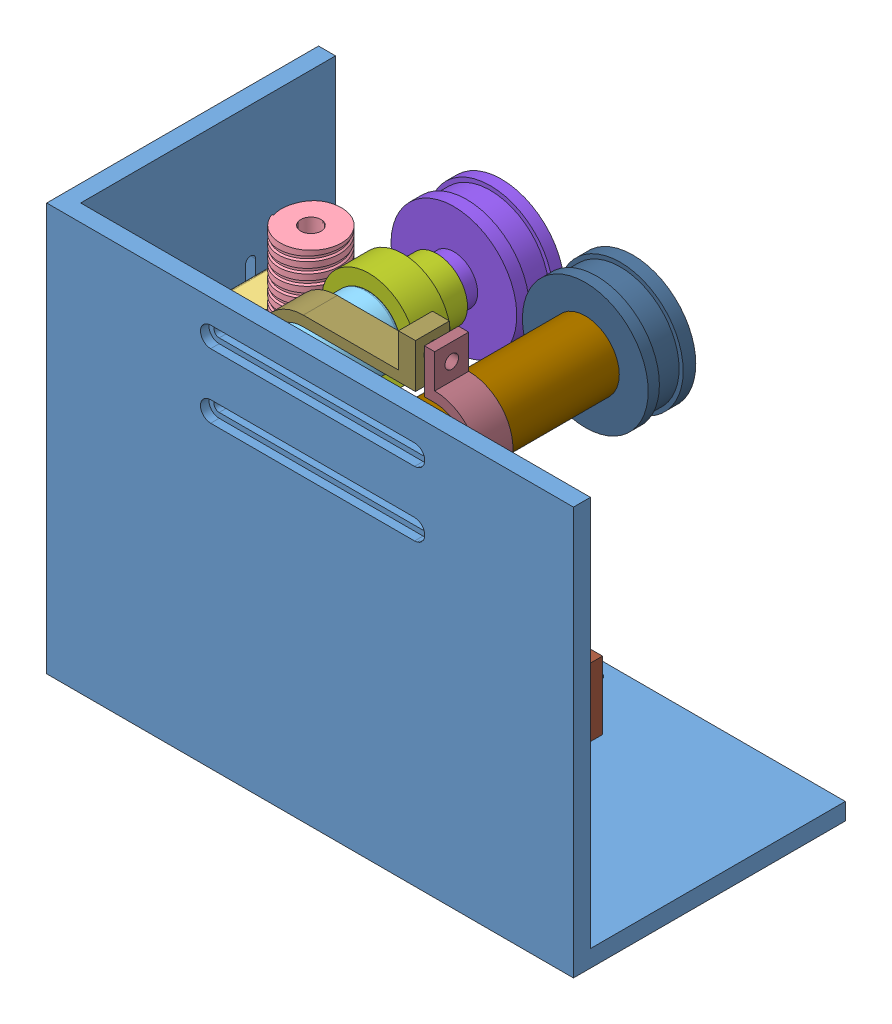
SolidWorks assembly 装配体2, configuration 默认. Lengths in mm.
Overall size (155 126.36 80).
18 component instances, 13 part files, 36 mates.
Components (placement in the parent):
- 支架-1: 支架 [默认] at origin size (155 120 80)
- 装配体-1: 装配体 [默认] at (30.5 -45.1244 40) x (-1 0 0) z (0 0 -1) size (45.5 73.2 40)
  - 电机-1: 电机 [默认] at origin size (36.5 73.2 36.5)
  - 电机支架-1: 电机支架 [默认] at (25.5 1.5 20) x (0 -1 0) z (0 0 -1) size (41 45.5 40)
- 蜗杆-1: 蜗杆 [默认] at (37.75 -38.8244 40) x (-0.943371 0 0.331739) z (0 1 0) size (18.01 18.93 32.45)
- 涡轮底座-1: 涡轮底座 [默认] at (72.3246 -7 72) x (0 -1 0) z (0 0 1) size (25 25 38)
- 轴承_8_12_3.5-2: 轴承_8_12_3.5 [默认] at (59.8246 -19.5 41) size (12 12 4)
- 蜗轮-2: 蜗轮 [默认] at (59.8246 -19.5 45) x (0.997228 0.0744 0) z (0 0 -1) size (28 28 20)
- 轮盘(3)-1: 轮盘(3) [默认] at (59.8246 -19.5 20) x (-0.591018 -0.806658 0) z (0 0 -1) size (37 37 31)
- 从动轮底座-1: 从动轮底座 [默认] at (85.9925 -7 72) size (25 25 67)
- 轮盘(1)-1: 轮盘(1) [默认] at (98.4925 -19.5 6) x (0.999997 0.002405 0) z (0 0 1) size (37 37 14)
- 轴承_8_12_3.5-4: 轴承_8_12_3.5 [默认] at (98.4925 -19.5 16) size (12 12 4)
- 深孔支架-1: 深孔支架 [默认] at (61.25 -115 23.6789) x (1 0 0) z (0 1 0) size (61 20 40)
- 轴承_8_12_3.5-3: 轴承_8_12_3.5 [默认] at (59.8246 -19.5 37) size (12 12 4)
- 轴承_8_12_3.5-5: 轴承_8_12_3.5 [默认] at (98.4925 -19.5 12) size (12 12 4)
- 轴承_8_12_3.5-6: 轴承_8_12_3.5 [默认] at (98.4925 -19.5 8) size (12 12 4)
- 紧固装置1-1: 紧固装置1 [默认] at (59.8246 -19.5 54.3149) size (46 46 10)
- 紧固装置2-1: 紧固装置2 [默认] at (98.4925 -19.5 64.3149) x (-1 0 0) z (0 0 -1) size (16 46 10)
Mates (geometry in assembly coordinates):
- 重合1: coincident anti-aligned: plane of 支架-1 through (5 0 80) normal (1 0 0); plane of 装配体-1/电机支架-1 through (5 -84.6244 20) normal (-1 0 0)
- 平行1: parallel aligned: plane of 支架-1 through (0 0 80) normal (0 1 0); plane of 装配体-1/电机支架-1 through (30.5 -43.6244 40) normal (0 1 0)
- 槽口1: slot anti-aligned: cylinder of 装配体-1/电机支架-1 through (5 -52.6244 55) axis (-1 0 0) radius 1.85; plane of 支架-1 through (-0.001 -40 53.5) normal (0 0 1); cylinder of 支架-1 through (-0.001 -80 55) axis (1 0 0) radius 1.5
- 重合3: coincident anti-aligned: plane of 装配体-1/电机-1 through (36.1423 -38.8244 40) normal (0 1 0); plane of 蜗杆-1 through (37.75 -38.8244 40) normal (0 -1 0)
- 同心4: concentric anti-aligned: cylinder of 装配体-1/电机-1 through (37.75 -38.8244 40) axis (0 1 0) radius 3; cylinder of 蜗杆-1 through (37.75 -6.3742 40) axis (0 -1 0) radius 3
- 槽口2: slot anti-aligned: cylinder of 装配体-1/电机支架-1 through (5 -76.6244 55) axis (-1 0 0) radius 1.85; cylinder of 支架-1 through (-0.001 -80 55) axis (1 0 0) radius 1.5; cylinder of 支架-1 through (-0.001 -40 55) axis (1 0 0) radius 1.5
- 槽口5: slot aligned: cylinder of 涡轮底座-1 through (50.3246 -29 75) axis (0 0 -1) radius 1.5; cylinder of 支架-1 through (108.25 -29 80) axis (0 0 -1) radius 1.5; cylinder of 支架-1 through (48.25 -29 80) axis (0 0 -1) radius 1.5
- 重合4: coincident anti-aligned: plane of 支架-1 through (155 0 75) normal (0 0 -1); plane of 涡轮底座-1 through (72.3246 -7 75) normal (0 0 1)
- 槽口6: slot aligned: cylinder of 涡轮底座-1 through (69.3246 -29 75) axis (0 0 -1) radius 1.5; cylinder of 支架-1 through (108.25 -29 80) axis (0 0 -1) radius 1.5; cylinder of 支架-1 through (48.25 -29 80) axis (0 0 -1) radius 1.5
- 重合5: coincident anti-aligned: plane of 涡轮底座-1 through (59.8246 -19.5 45) normal (0 0 -1); plane of 轴承_8_12_3.5-2 through (59.8246 -19.5 45) normal (0 0 1)
- 同心10: concentric aligned: cylinder of 轴承_8_12_3.5-2 through (59.8246 -19.5 45) axis (0 0 -1) radius 6; cylinder of 蜗轮-2 through (59.8246 -19.5 45) axis (0 0 -1) radius 6
- 同心11: concentric anti-aligned: cylinder of 涡轮底座-1 through (59.8246 -19.5 37) axis (0 0 1) radius 3.05; cylinder of 轴承_8_12_3.5-2 through (59.8246 -19.5 45) axis (0 0 -1) radius 3
- 重合7: coincident anti-aligned: plane of 涡轮底座-1 through (59.8246 -19.5 45) normal (0 0 -1); plane of 蜗轮-2 through (59.8246 -19.5 45) normal (0 0 1)
- 同心12: concentric aligned: cylinder of 蜗轮-2 through (59.8246 -19.5 45) axis (0 0 -1) radius 6; cylinder of 轮盘(3)-1 through (59.8246 -19.5 37) axis (0 0 -1) radius 6
- 槽口7: slot aligned: cylinder of 从动轮底座-1 through (107.9925 -29 75) axis (0 0 -1) radius 1.5; cylinder of 支架-1 through (108.25 -29 80) axis (0 0 -1) radius 1.5; cylinder of 支架-1 through (48.25 -29 80) axis (0 0 -1) radius 1.5
- 槽口8: slot aligned: cylinder of 从动轮底座-1 through (107.9925 -10 75) axis (0 0 -1) radius 1.5; cylinder of 支架-1 through (108.25 -10 80) axis (0 0 -1) radius 1.5; cylinder of 支架-1 through (48.25 -10 80) axis (0 0 -1) radius 1.5
- 重合9: coincident anti-aligned: plane of 支架-1 through (155 0 75) normal (0 0 -1); plane of 从动轮底座-1 through (85.9925 -7 75) normal (0 0 1)
- 重合10: coincident anti-aligned: plane of 从动轮底座-1 through (98.4925 -19.5 20) normal (0 0 -1); plane of 轴承_8_12_3.5-4 through (98.4925 -19.5 20) normal (0 0 1)
- 重合11: coincident anti-aligned: plane of 从动轮底座-1 through (98.4925 -19.5 20) normal (0 0 -1); plane of 轮盘(1)-1 through (98.4925 -19.5 20) normal (0 0 1)
- 槽口9: slot anti-aligned: cylinder of 深孔支架-1 through (66.25 -95 27.6789) axis (0 -1 0) radius 1.5; plane of 支架-1 through (67.75 -120 5) normal (-1 0 0); cylinder of 支架-1 through (66.25 -120 5) axis (0 1 0) radius 1.5
- 槽口10: slot anti-aligned: cylinder of 深孔支架-1 through (86.25 -95 39.6789) axis (0 -1 0) radius 1.5; cylinder of 支架-1 through (86.25 -120 65) axis (0 1 0) radius 1.8599; cylinder of 支架-1 through (86.25 -120 5) axis (0 1 0) radius 1.8599
- 重合12: coincident anti-aligned: plane of 支架-1 through (155 -115 80) normal (0 1 0); plane of 深孔支架-1 through (61.25 -115 23.6789) normal (0 -1 0)
- 重合13: coincident anti-aligned: plane of 轴承_8_12_3.5-2 through (59.8246 -19.5 41) normal (0 0 -1); plane of 轴承_8_12_3.5-3 through (59.8246 -19.5 41) normal (0 0 1)
- 同心16: concentric anti-aligned: cylinder of 涡轮底座-1 through (59.8246 -19.5 37) axis (0 0 1) radius 3.05; cylinder of 轴承_8_12_3.5-3 through (59.8246 -19.5 41) axis (0 0 -1) radius 3
- 重合14: coincident anti-aligned: plane of 涡轮底座-1 through (59.8246 -19.5 37) normal (0 0 -1); plane of 轮盘(3)-1 through (59.8246 -19.5 37) normal (0 0 1)
- 同心17: concentric anti-aligned: cylinder of 从动轮底座-1 through (98.4925 -19.5 8) axis (0 0 1) radius 3.05; cylinder of 轴承_8_12_3.5-4 through (98.4925 -19.5 20) axis (0 0 -1) radius 3
- 重合15: coincident anti-aligned: plane of 轴承_8_12_3.5-4 through (98.4925 -19.5 16) normal (0 0 -1); plane of 轴承_8_12_3.5-5 through (98.4925 -19.5 16) normal (0 0 1)
- 同心18: concentric anti-aligned: cylinder of 从动轮底座-1 through (98.4925 -19.5 8) axis (0 0 1) radius 3.05; cylinder of 轴承_8_12_3.5-5 through (98.4925 -19.5 16) axis (0 0 -1) radius 3
- 重合16: coincident anti-aligned: plane of 轴承_8_12_3.5-5 through (98.4925 -19.5 12) normal (0 0 -1); plane of 轴承_8_12_3.5-6 through (98.4925 -19.5 12) normal (0 0 1)
- 同心19: concentric anti-aligned: cylinder of 从动轮底座-1 through (98.4925 -19.5 8) axis (0 0 1) radius 3.05; cylinder of 轴承_8_12_3.5-6 through (98.4925 -19.5 12) axis (0 0 -1) radius 3
- 同心20: concentric aligned: cylinder of 轮盘(1)-1 through (98.4925 -19.5 20) axis (0 0 -1) radius 6; cylinder of 轴承_8_12_3.5-4 through (98.4925 -19.5 20) axis (0 0 -1) radius 6
- 同心21: concentric anti-aligned: cylinder of 涡轮底座-1 through (59.8246 -19.5 45) axis (0 0 1) radius 10; cylinder of 紧固装置1-1 through (59.8246 -19.5 64.3149) axis (0 0 -1) radius 10
- 平行2: parallel aligned: plane of 支架-1 through (5 0 80) normal (1 0 0); plane of 紧固装置1-1 through (92.8246 3.5 64.3149) normal (1 0 0)
- 平行4: parallel anti-aligned: plane of 支架-1 through (5 0 80) normal (1 0 0); plane of 紧固装置2-1 through (95.4925 3.5 54.3149) normal (-1 0 0)
- 同心24: concentric aligned: cylinder of 从动轮底座-1 through (98.4925 -19.5 20) axis (0 0 1) radius 10; cylinder of 紧固装置2-1 through (98.4925 -19.5 54.3149) axis (0 0 1) radius 10
- 重合22: coincident aligned: plane of 紧固装置1-1 through (59.8246 -19.5 54.3149) normal (0 0 -1); plane of 紧固装置2-1 through (98.4925 -19.5 54.3149) normal (0 0 -1)
